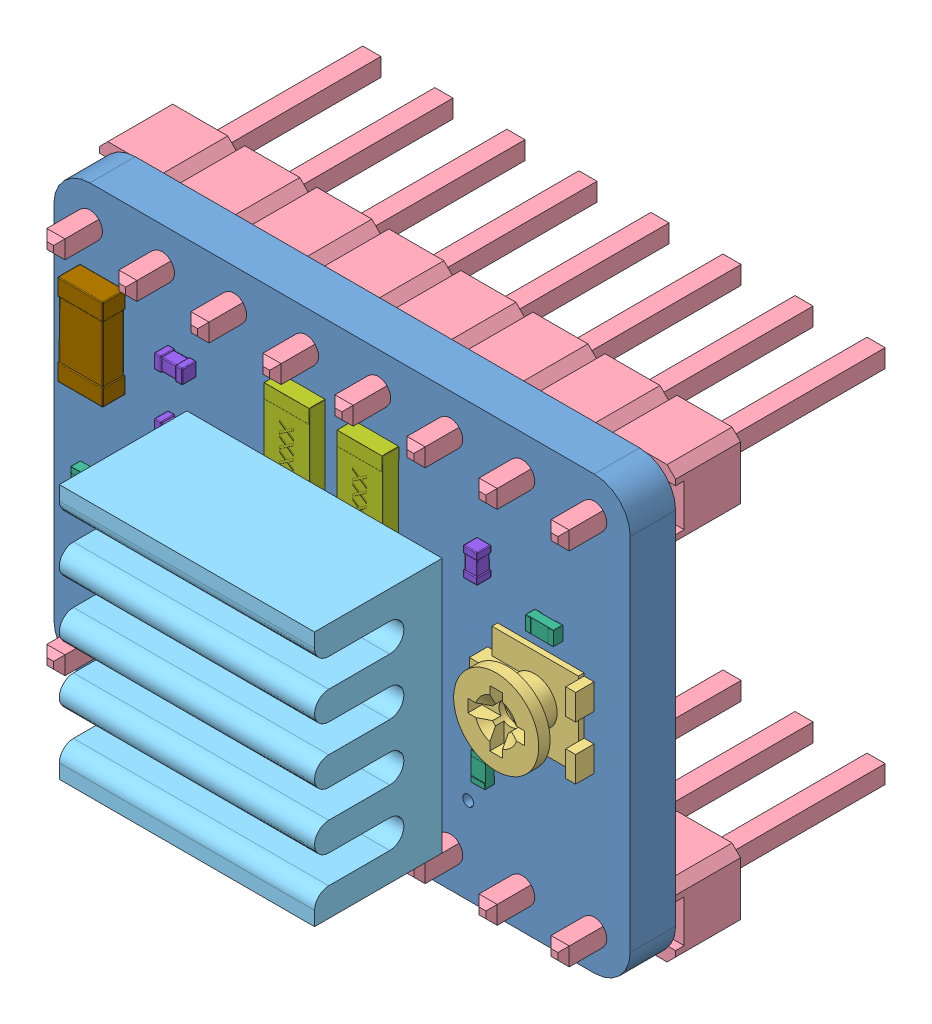
SolidWorks assembly A4988-1, configuration Défaut. Lengths in mm.
Overall size (20.32 15.24 15.96).
19 component instances, 9 part files, 0 mates.
Components (placement in the parent):
- stepstick-1: stepstick [Défaut] at origin size (20.32 15.24 1.6)
- QFN28ET_A4983-1: QFN28ET_A4983 [Défaut] at (60.96 57.15 1.6) size (5 5 0.9)
- TRIMPOT3MM_TRIMPOTSMD-1: TRIMPOT3MM_TRIMPOTSMD [Défaut] at (67.945 58.293 1.6) x (0 1 0) z (0 0 1) size (3 3.75 1.55)
- Pin header pitch 2.54mm_08 contacts-1: Pin header pitch 2.54mm_08 contacts [Défaut] at (69.85 52.07 -2.29) x (-1 0 0) z (0 0 -1) size (20.32 2.49 11.54)
- Pin header pitch 2.54mm_08 contacts-2: Pin header pitch 2.54mm_08 contacts [Défaut] at (69.85 64.77 -2.29) x (-1 0 0) z (0 0 -1) size (20.32 2.49 11.54)
- Heatsink For A4988-1: Heatsink For A4988 [Défaut] at (61.3133 57.6122 2.4232) x (0 1 0) z (1 0 0) size (9 5 9)
- R0402-01-1: R0402-01 [Défaut] at (68.2722 60.6475 1.6131) x (1 0 0) z (0 -1 0) size (1.08 0.42 0.58)
- R0402-01-2: R0402-01 [Défaut] at (66.0925 55.3045 1.5976) x (0 -1 0) z (-1 0 0) size (1.08 0.42 0.58)
- R0402-01-3: R0402-01 [Défaut] at (63.5962 53.8945 1.5922) x (-1 0 0) z (0 1 0) size (1.08 0.42 0.58)
- R1206-01-1: R1206-01 [Défaut] at (62.3168 62.0471 1.7448) x (0 -1 0) z (-1 0 0) size (3.18 0.68 1.67)
- R1206-01-2: R1206-01 [Défaut] at (59.5663 62.032 1.5671) x (0 -1 0) z (-1 0 0) size (3.18 0.68 1.67)
- R0402-01-4: R0402-01 [Défaut] at (52.1553 57.0656 1.7677) x (0 -1 0) z (-1 0 0) size (1.08 0.42 0.58)
- C0402-1: C0402 [Défaut] at (57.1293 54.2576 1.8326) size (1 0.55 0.53)
- C0402-2: C0402 [Défaut] at (54.5698 55.4202 1.8561) size (1 0.55 0.53)
- C0402-3: C0402 [Défaut] at (65.7234 61.5632 1.8516) x (0 -1 0) z (0 0 1) size (1 0.55 0.53)
- C0402-4: C0402 [Défaut] at (55.3576 60.0066 1.8835) size (1 0.55 0.53)
- C0402-5: C0402 [Défaut] at (56.5915 56.9455 1.8091) x (0 -1 0) z (0 0 1) size (1 0.55 0.53)
- C0402-6: C0402 [Défaut] at (55.3483 62.0044 1.8729) size (1 0.55 0.53)
- C1206B-1: C1206B [Défaut] at (52.5232 61.8008 1.6006) x (0 -1 0) z (-1 0 0) size (3.2 0.85 1.63)
